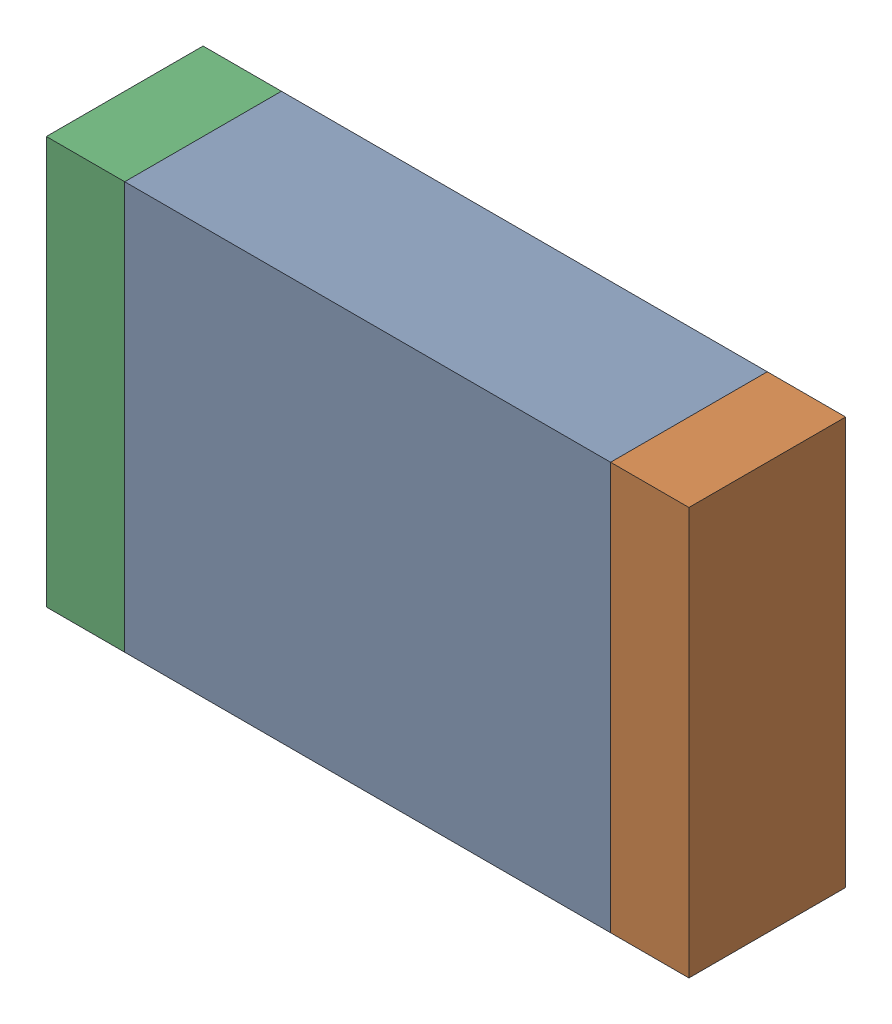
SolidWorks assembly C52, configuration Default. Lengths in mm.
Overall size (2.05 1.3 0.5).
6 component instances, 2 part files, 0 mates.
Components (placement in the parent):
- 836756464-1: 836756464 [Default] at (124.875 45.3 0) size (1.55 1.3 0.5)
  - Extruded_42-1: Extruded_42 [Default] at origin size (1.55 1.3 0.5)
- 836756336-1: 836756336 [Default] at (125.775 45.3 0) size (0.25 1.3 0.5)
  - Extruded_41-1: Extruded_41 [Default] at origin size (0.25 1.3 0.5)
- 836756336-2: 836756336 [Default] at (123.975 45.3 0) size (0.25 1.3 0.5)
  - Extruded_41-1: Extruded_41 [Default] at origin size (0.25 1.3 0.5)
